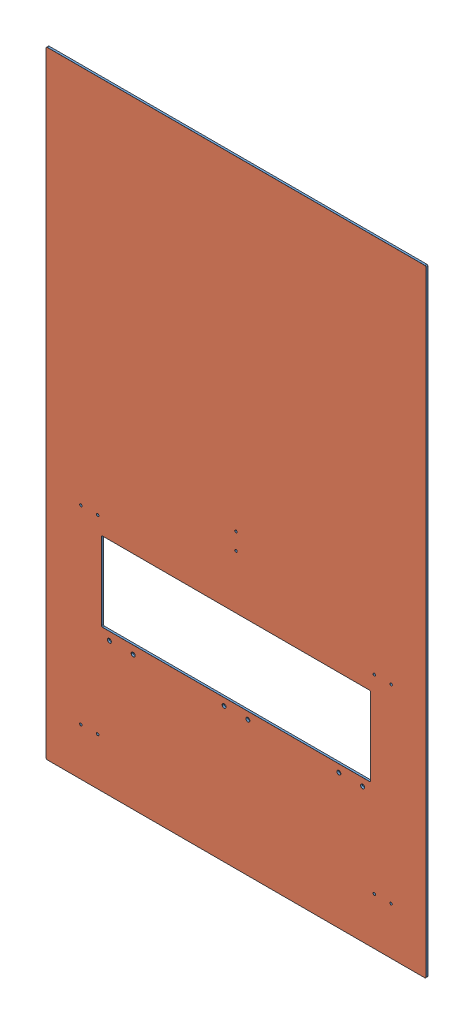
SolidWorks assembly GE-20321, configuration GE-20321-Red. Lengths in mm.
Overall size (1219.2 1981.2 6.6).
2 component instances, 2 part files, 6 mates.
Components (placement in the parent):
- GE-20314-1: GE-20314 [Default] at (-609.6 0 0) size (1219.2 1981.2 6.35)
- GE-20321-Vinyl-1: GE-20321-Vinyl [GE-20321-Red-Vinyl] at (-609.6 0 0.254) size (1219.2 1981.2 0.25)
Mates (geometry in assembly coordinates):
- Coincident1: coincident anti-aligned: plane of GE-20314-1 through (-609.6 0 6.35) normal (0 0 1); plane of GE-20321-Vinyl-1 through (-609.6 1981.2 6.35) normal (0 0 -1)
- Coincident2: coincident aligned: plane of GE-20314-1 through (609.6 0 6.35) normal (1 0 0); plane of GE-20321-Vinyl-1 through (609.6 0 6.604) normal (1 0 0)
- Coincident3: coincident aligned: plane of GE-20314-1 through (-609.6 1981.2 6.35) normal (0 1 0); plane of GE-20321-Vinyl-1 through (-609.6 1981.2 6.604) normal (0 1 0)
- Coincident4: coincident anti-aligned: plane of GE-20314-1 through (-609.6 0 0) normal (0 0 -1)
- Coincident5: coincident anti-aligned: plane of GE-20314-1 through (-609.6 0 6.35) normal (0 -1 0)
- Symmetric1: symmetric aligned: plane of GE-20314-1 through (609.6 0 6.35) normal (1 0 0); plane of GE-20314-1 through (-609.6 0 6.35) normal (-1 0 0)
